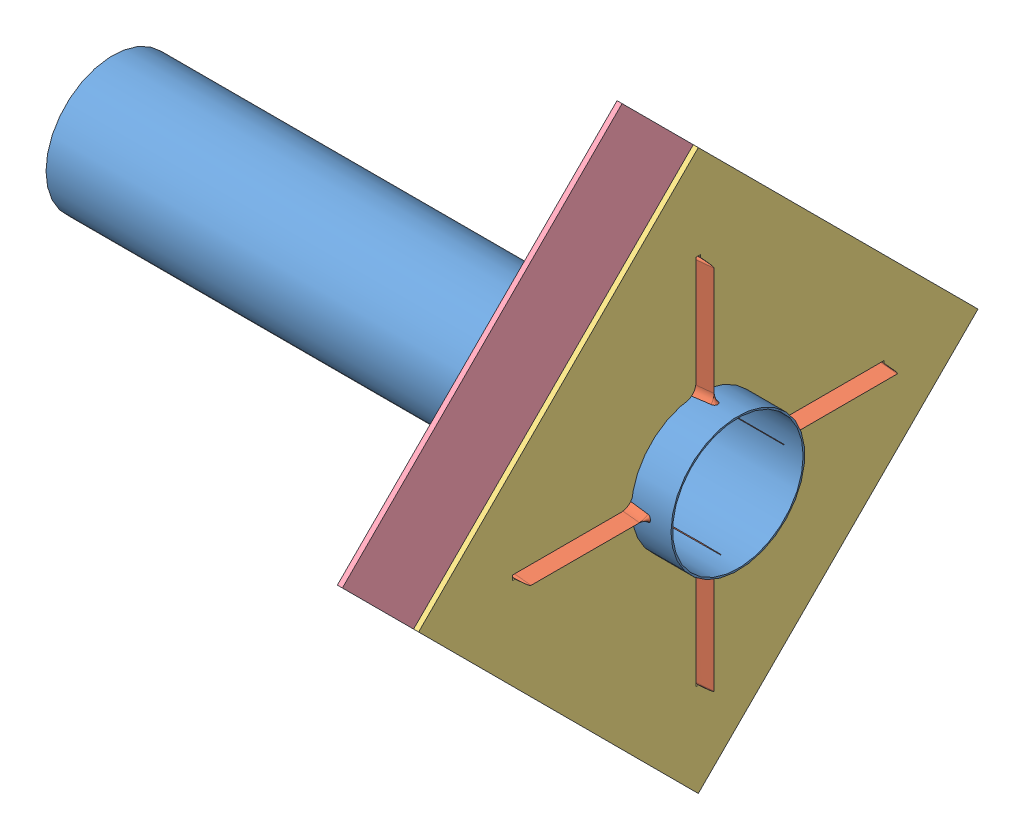
SolidWorks assembly Assem, configuration Default. Lengths in mm.
Overall size (790 707.11 707.11).
8 component instances, 4 part files, 6 mates.
Components (placement in the parent):
- Tube_Fin Assem V2-1: Tube_Fin Assem V2 [Default] at (3.3082 3.1622 -3.894) size (790 472.21 472.21)
  - Lower body tube-1: Lower body tube [Default] at (-419.5819 4.5927 9.8514) size (790 169.1 169.1)
  - Fin 150_75_150 curved-1: Fin 150_75_150 curved [Default] at (190.2852 4.5927 -69.6486) x (1 0 0) z (0 0 -1) size (164.95 35.88 158.03)
  - Fin 150_75_150 curved-2: Fin 150_75_150 curved [Default] at (190.2852 84.0927 9.8514) x (1 0 0) z (0 1 0) size (164.95 35.88 158.03)
  - Fin 150_75_150 curved-3: Fin 150_75_150 curved [Default] at (190.2852 4.5927 89.3514) size (164.95 35.88 158.03)
  - Fin 150_75_150 curved-4: Fin 150_75_150 curved [Default] at (190.2852 -74.9073 9.8514) x (1 0 0) z (0 -1 0) size (164.95 35.88 158.03)
- Back-1: Back [Default] at (317.3762 102.1493 -20.5016) x (0 -0.707107 -0.707107) z (0 -0.707107 0.707107) size (500 6.35 500)
- Front-1: Front [Default] at (221.0262 -33.5881 18.7879) x (0 0.707107 0.707107) z (0 0.707107 -0.707107) size (500 6.35 500)
Mates (geometry in assembly coordinates):
- Concentric1: concentric anti-aligned: cylinder of Tube_Fin Assem V2-1/Lower body tube-1 through (373.7262 7.7549 5.9573) axis (-1 0 0) radius 84.55; cylinder of Back-1 through (317.3762 7.7549 5.9573) axis (1 0 0) radius 84
- Angle1: planar angle = 0.785398 rad aligned: plane of Tube_Fin Assem V2-1/Fin 150_75_150 curved-3 through (268.5843 7.7549 240.4573) normal (0 0 1); plane of Back-1 through (323.7262 7.7549 359.5107) normal (0 -0.707107 0.707107)
- Distance1: distance = 50 mm aligned: plane of Tube_Fin Assem V2-1 through (373.7262 3.1622 -3.894) normal (1 0 0); plane of Back-1 through (323.7262 102.1493 -20.5016) normal (1 0 0)
- Concentric2: concentric anti-aligned: cylinder of Tube_Fin Assem V2-1/Lower body tube-1 through (373.7262 7.7549 5.9573) axis (-1 0 0) radius 84.55; cylinder of Front-1 through (221.0262 7.7549 5.9573) axis (1 0 0) radius 84
- Coincident4: coincident aligned: plane of Back-1 through (323.7262 7.7549 359.5107) normal (0 -0.707107 0.707107); plane of Front-1 through (227.3762 -345.7985 5.9573) normal (0 -0.707107 0.707107)
- Distance2: distance = 90 mm anti-aligned: plane of Front-1 through (227.3762 -33.5881 18.7879) normal (1 0 0); plane of Back-1 through (317.3762 102.1493 -20.5016) normal (-1 0 0)
